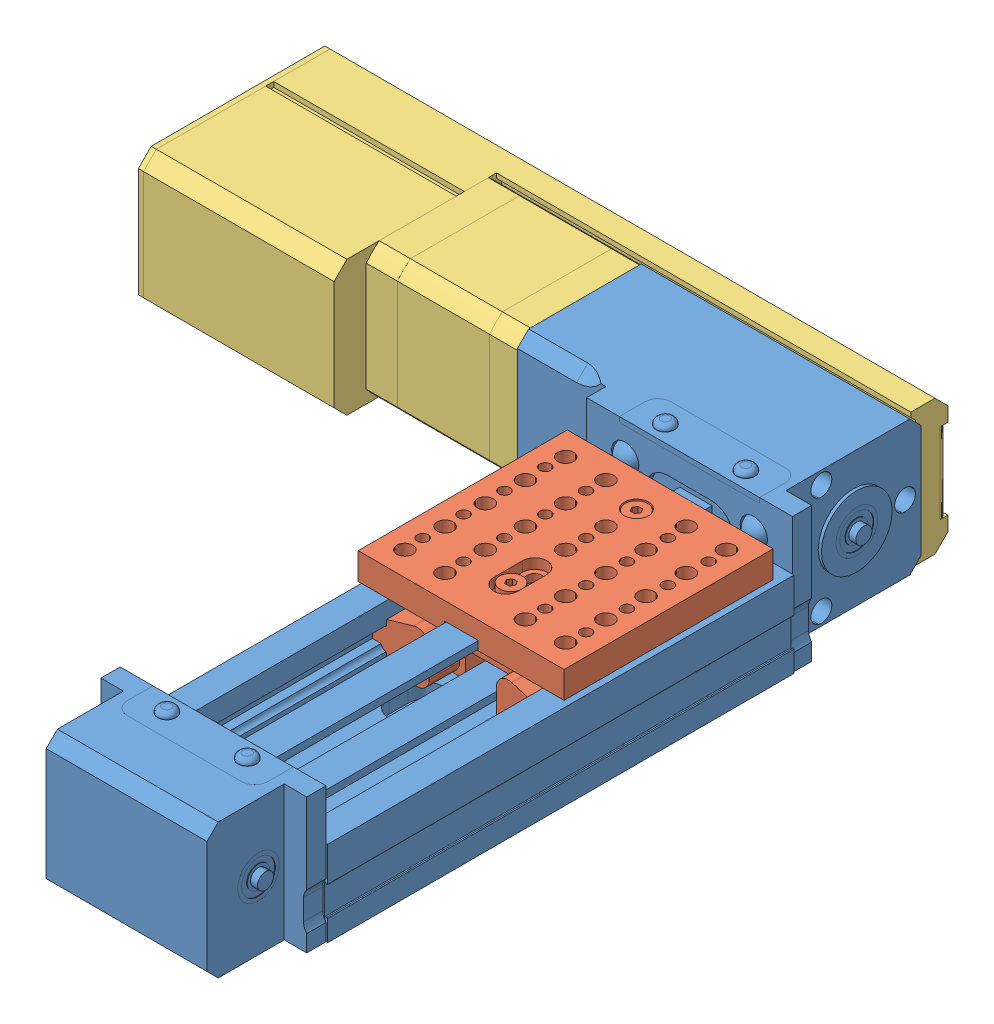
SolidWorks assembly BLQ, configuration BLQ0070-E01T3A. Lengths in mm.
Overall size (204.61 44.15 235.2).
3 component instances, 3 part files, 8 mates.
Components (placement in the parent):
- BLQ_base^BLQ-1: BLQ_base^BLQ [BLQ0070] at origin size (92 44.15 223) (virtual)
- BLQ_carriage^BLQ-1: BLQ_carriage^BLQ [Standard] at origin size (64 28.1 65) (virtual)
- NMS17_motor^BLQ-1: NMS17_motor^BLQ [BLQ-E01T3A] at (-59.5 21.5 0) x (0 0 -1) z (1 0 0) size (64.2 42 194.41) (virtual)
Mates (geometry in assembly coordinates):
- Coincident1: coincident anti-aligned: plane of BLQ_base^BLQ-1 through (-59.5 0 0) normal (-1 0 0); plane of NMS17_motor^BLQ-1 through (-59.5 21.5 0) normal (1 0 0)
- Coincident2: coincident anti-aligned: plane of NMS17_motor^BLQ-1 through (-59.5 21.5 0) normal (0 0 -1); plane of assembly through (0 0 0) normal (0 0 1)
- Concentric1: concentric aligned: cylinder of BLQ_base^BLQ-1 through (25 21.5 0) axis (-1 0 0) radius 11; cylinder of NMS17_motor^BLQ-1 through (-58 21.5 0) axis (-1 0 0) radius 11
- Coincident3: coincident anti-aligned: plane of BLQ_base^BLQ-1 through (59.5 0 0) normal (1 0 0); plane of NMS17_motor^BLQ-1 through (59.5 21.5 0) normal (-1 0 0)
- Concentric2: concentric: cylinder of BLQ_base^BLQ-1 through (-25 21.5 0) axis (1 0 0) radius 11; point of NMS17_motor^BLQ-1
- Coincident5: coincident aligned: plane of BLQ_carriage^BLQ-1 through (0 0 0) normal (1 0 0); plane of assembly through (0 0 0) normal (1 0 0)
- Coincident6: coincident aligned: plane of BLQ_carriage^BLQ-1 through (0 0 0) normal (0 1 0); plane of assembly through (0 0 0) normal (0 1 0)
- LimitDistance1: limit distance = 0 mm aligned: plane of BLQ_carriage^BLQ-1 through (0 0 0) normal (0 0 1); plane of assembly through (0 0 0) normal (0 0 1)
